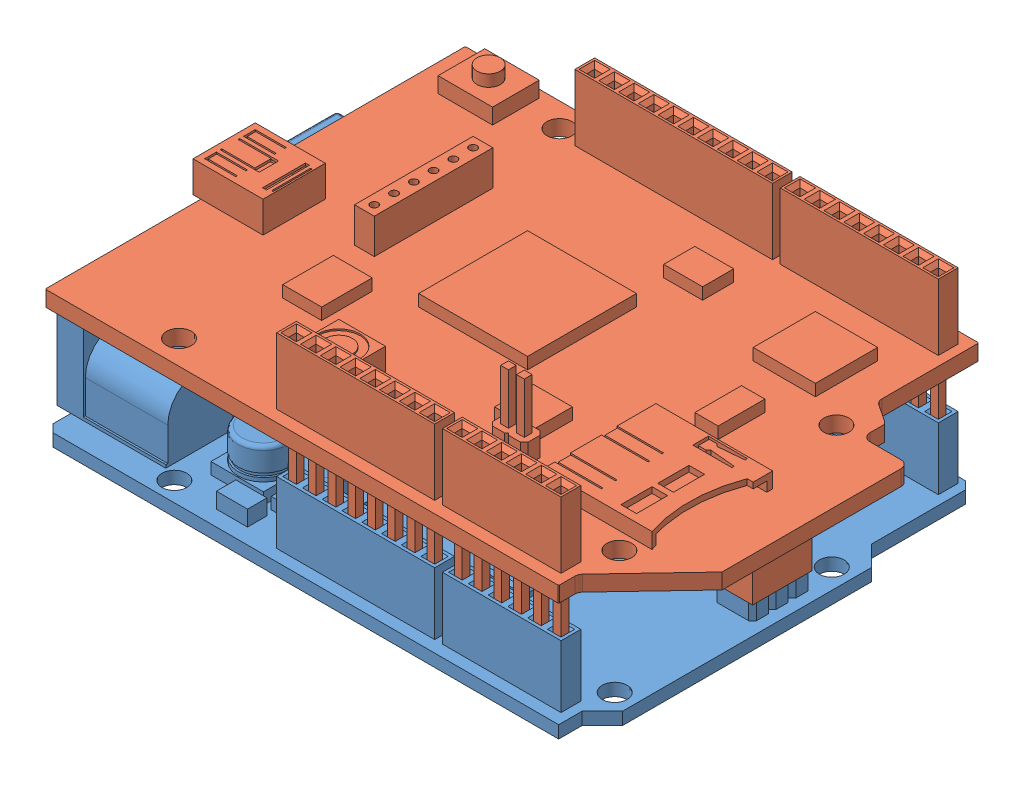
SolidWorks assembly A_Arduino_Uno_Wifi_Shield, configuration Défaut. Lengths in mm.
Overall size (81.2 26.1 54).
2 component instances, 2 part files, 4 mates.
Components (placement in the parent):
- Arduino UNO-1: Arduino UNO [Default] at origin size (74.8 12.1 53.3)
- Arduino_Wifi_Shield-1: Arduino_Wifi_Shield [Défaut] at (-33.0002 15.1 -27.35) x (0 0 1) z (-1 0 0) size (54 22.5 76)
Mates (geometry in assembly coordinates):
- Coïncidente2: coordinate: point of Arduino UNO-1; point of assembly
- Coïncidente3: coincident anti-aligned: plane of Arduino UNO-1 through (31.0298 9.6 24.38) normal (0 0 -1); plane of Arduino_Wifi_Shield-1 through (30.0298 2.1858 24.38) normal (0 0 1)
- Coïncidente4: coincident anti-aligned: plane of Arduino UNO-1 through (31.0298 9.6 24.38) normal (-1 0 0); plane of Arduino_Wifi_Shield-1 through (31.0298 2.1858 24.38) normal (1 0 0)
- Coïncidente5: coincident anti-aligned: plane of Arduino UNO-1 through (29.06 3.6 -4.75) normal (0 1 0); plane of Arduino_Wifi_Shield-1 through (-33.0002 3.6 -27.35) normal (0 -1 0)
